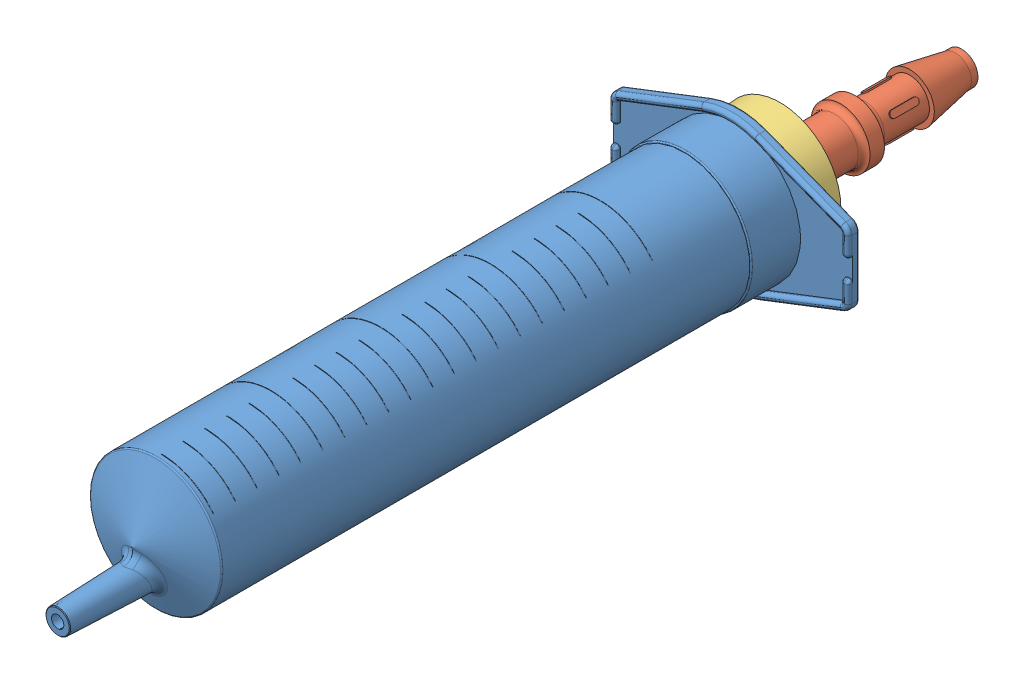
SolidWorks assembly Pneumatic Syringe Assembly, configuration Default. Lengths in mm.
Overall size (39 25 147.25).
3 component instances, 3 part files, 4 mates.
Components (placement in the parent):
- body 20ml-2: body 20ml [Défaut] at (69.5833 29.2152 -42.0082) size (39 25 111)
- HoseBarb_025in_2653K130-1: HoseBarb_025in_2653K130 [2653K13] at (69.5833 29.2152 -149.7669) x (0 0 -1) z (-0.201469 -0.979495 0) size (46.99 9.6 9.6)
- rubber_stopper_9545K116-2: rubber_stopper_9545K116 [Default] at (69.5833 29.2152 -118.2582) x (-0.265748 -0.964043 0) z (0.964043 -0.265748 0) size (19.84 25.4 19.84)
Mates (geometry in assembly coordinates):
- Concentric1: concentric aligned: cylinder of body 20ml-2 through (69.5833 29.2152 -149.2015) axis (0 0 -1) radius 9.75; cylinder of rubber_stopper_9545K116-2 through (69.5833 29.2152 -118.2582) axis (0 0 -1) radius 3.175
- Coincident1: coincident: circle of body 20ml-2; cone of rubber_stopper_9545K116-2 through (69.5833 29.2152 -118.2582) axis (0 0 1)
- Concentric2: concentric anti-aligned: cylinder of HoseBarb_025in_2653K130-1 through (69.5833 29.2152 -149.7669) axis (0 0 1) radius 2.1209; cylinder of rubber_stopper_9545K116-2 through (69.5833 29.2152 -118.2582) axis (0 0 -1) radius 3.175
- Tangent2: tangent: torus of HoseBarb_025in_2653K130-1; plane of rubber_stopper_9545K116-2 through (60.0182 31.8519 -143.6582) normal (0 0 -1)
